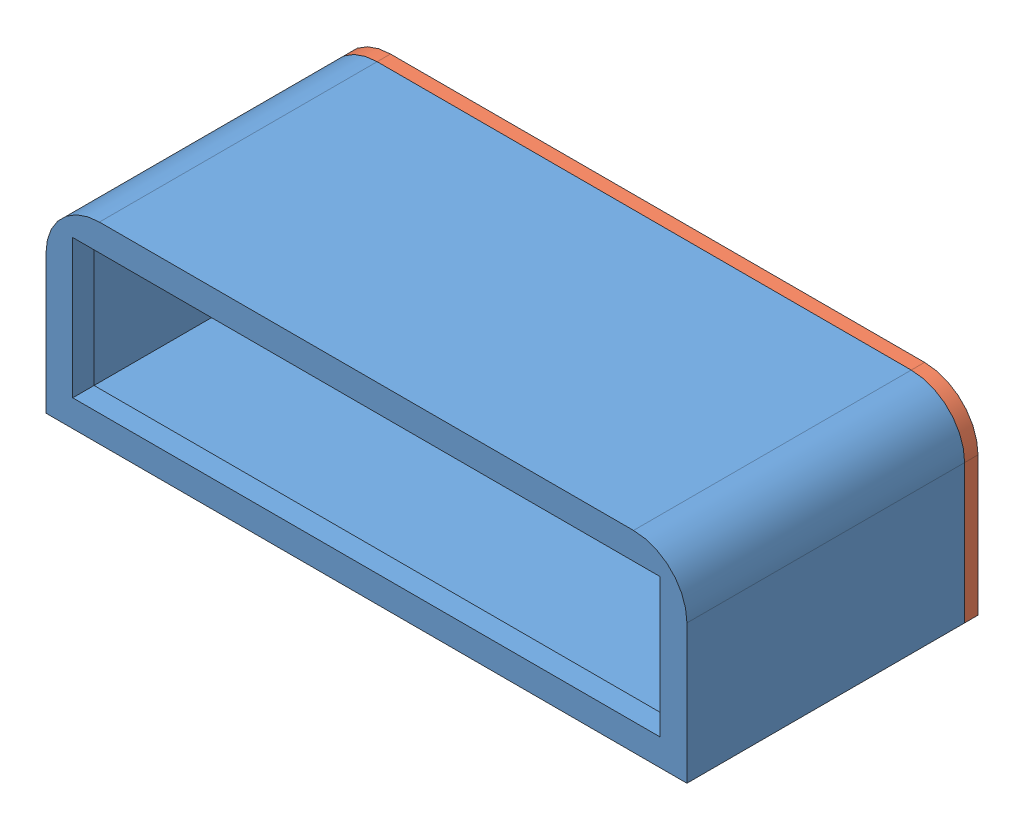
SolidWorks assembly Assem1, configuration Default. Lengths in mm.
Overall size (152.4 45.72 69.21).
2 component instances, 2 part files, 3 mates.
Components (placement in the parent):
- housing-1: housing [Default] at (66.2592 87.075 106.9088) size (152.4 45.72 66.04)
- housing_back_plate-1: housing_back_plate [Default] at (66.2592 87.075 103.7338) size (152.4 45.72 3.17)
Mates (geometry in assembly coordinates):
- Concentric1: concentric: circle of housing-1; circle of housing_back_plate-1
- Concentric2: concentric: circle of housing-1; circle of housing_back_plate-1
- Coincident1: coincident anti-aligned: plane of housing-1 through (66.2592 87.075 106.9088) normal (0 0 -1); plane of housing_back_plate-1 through (66.2592 87.075 106.9088) normal (0 0 1)
